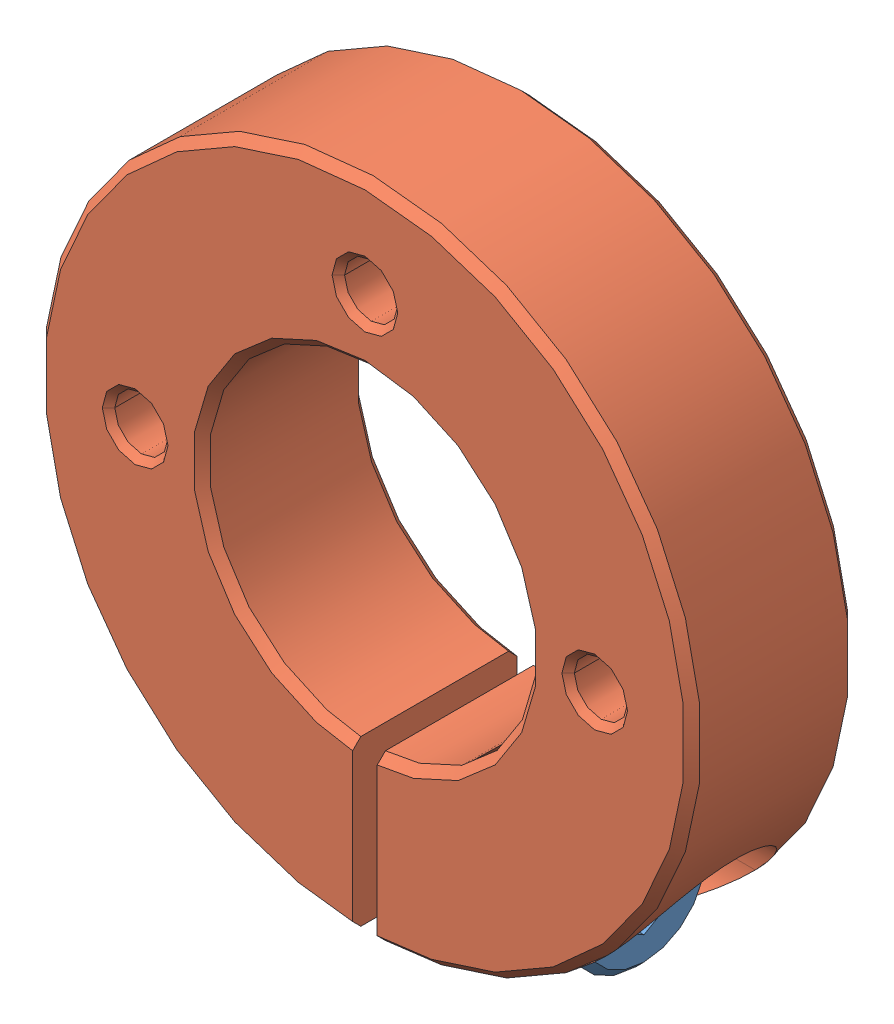
SolidWorks assembly SCSTR20_10, configuration 20mm 3 Hole Shaft Collar. Lengths in mm.
Overall size (40 39.99 10).
2 component instances, 2 part files, 0 mates.
Components (placement in the parent):
- SCSTR20_10_3-1: SCSTR20_10_3 [Default] at (7 -14 0) x (-1 0 0) z (0 0 1) size (25 8.5 8.5)
- SCSTR20_10_5-1: SCSTR20_10_5 [Default] at origin size (40 39.99 10)
